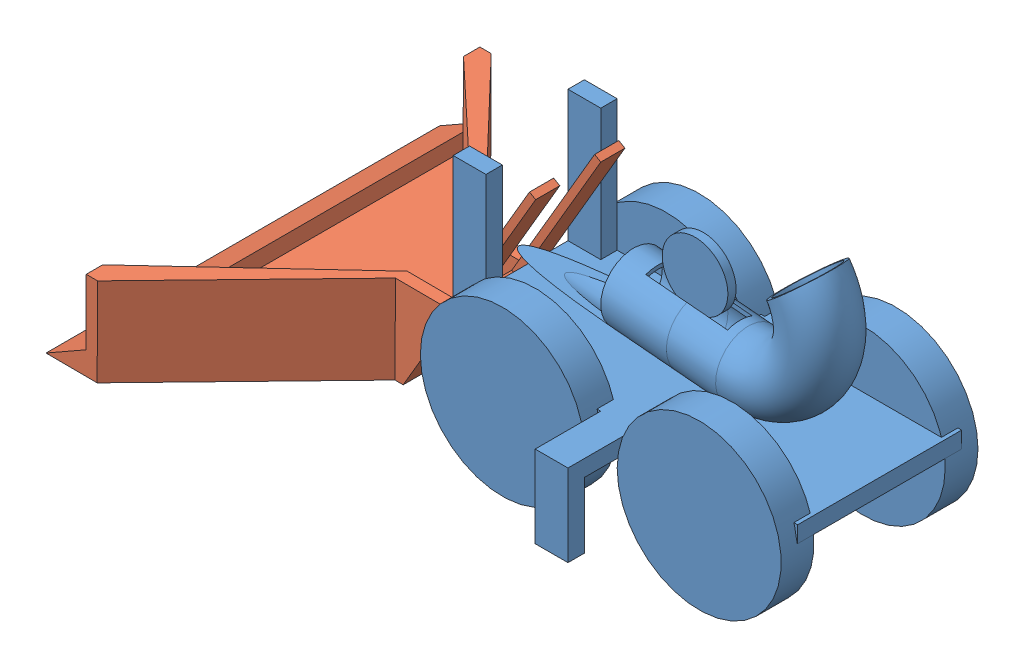
SolidWorks assembly Assembly, configuration Default. Lengths in mm.
Overall size (498.1 389.59 304.8).
2 component instances, 2 part files, 6 mates.
Components (placement in the parent):
- chassis-1: chassis [Default] at (-172.256 113.4851 134.4222) size (287.96 387.35 228.6)
- scoop-2: scoop [Default] at (-229.9988 130.8786 99.8405) x (0 0 1) z (-0.999985 0.005399 0) size (304.8 178.73 260.35)
Mates (geometry in assembly coordinates):
- Parallel3: parallel: plane of chassis-1 through (925.1771 202.3851 350.3222) normal (0 -1 0); plane of scoop-2
- Parallel4: parallel: line of chassis-1 through (107.144 215.0851 312.2222) axis (0 0 -1); line of scoop-2 through (-227.0384 135.9427 277.6405) axis (0 0 -1)
- Coincident10: coincident: line of chassis-1 through (-159.556 240.4851 286.8222) axis (0 0 -1); plane of scoop-2 through (-223.6488 130.8443 -39.5749) normal (0.863313 -0.504668 0)
- Coincident12: coincident: plane of chassis-1 through (-172.256 316.6851 286.8222) normal (0 0 -1); plane of scoop-2 through (-153.4296 199.0462 286.8222) normal (0 0 1)
- Coincident13: coincident: line of chassis-1 through (-159.556 240.4851 286.8222) axis (0 0 -1); line of scoop-2 through (-159.556 240.4851 286.8222) axis (0 0 -1)
- Tangent2: tangent: cylinder of chassis-1 through (-108.756 196.0351 324.9222) axis (0 0 -1) radius 63.5; plane of scoop-2
